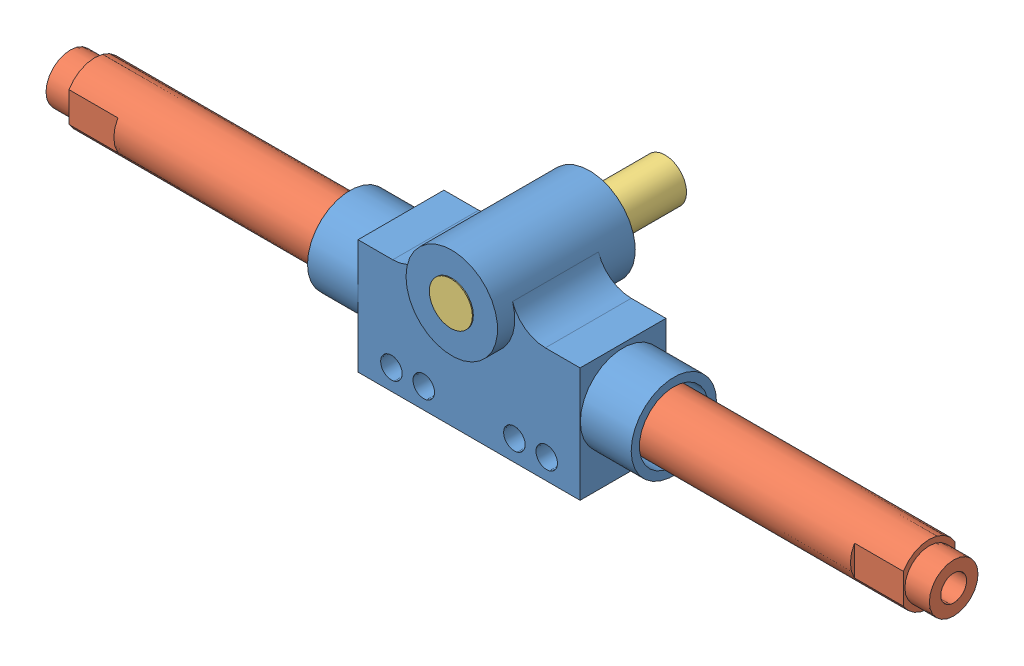
SolidWorks assembly SteeringRack, configuration Default. Lengths in mm.
Overall size (296 62.5 80.5).
3 component instances, 3 part files, 9 mates.
Components (placement in the parent):
- SteeringRackCasting-1: SteeringRackCasting [Default] at (-167.3912 -210.4134 -15.8) size (131.76 62.5 52.7)
- SteeringRackGear-1: SteeringRackGear [Default] at origin size (296 21.6 21.6)
- SteeringPinionGear-1: SteeringPinionGear [Default] at (0 20.65 22.5) x (0 0 -1) z (1 0 0) size (172.28 15.88 15.88)
Mates (geometry in assembly coordinates):
- Coincident1: coincident: plane of SteeringRackCasting-1 through (0 -210.4134 -15.8) normal (1 0 0); plane of assembly through (0 0 0) normal (1 0 0)
- Coincident2: coincident: line of SteeringRackCasting-1 through (131.76 65.88 0) axis (0 -1 0); plane of assembly
- Parallel1: parallel: plane of SteeringRackCasting-1 through (-167.3912 -210.4134 -15.8) normal (0 1 0); plane of assembly through (0 0 0) normal (0 1 0)
- Coincident4: coincident: line of SteeringRackCasting-1 through (131.76 65.88 0) axis (0 -1 0); plane of assembly
- Concentric1: concentric: cylinder of SteeringRackCasting-1 through (-59.55 0 0) axis (1 0 0) radius 12.7; cylinder of SteeringRackGear-1 through (-180.4724 0 0) axis (-1 0 0) radius 10.8
- Distance1: distance = 0 mm: plane of SteeringRackGear-1 through (0 0 0) normal (1 0 0); plane of assembly through (0 0 0) normal (1 0 0)
- Coincident6: coincident: plane of SteeringRackGear-1 through (0 0 0) normal (0 0 1); plane of assembly through (0 0 0) normal (0 0 1)
- Concentric2: concentric: cylinder of SteeringRackCasting-1 through (0 20.65 22.15) axis (0 0 -1) radius 7.9375; cylinder of SteeringPinionGear-1 through (0 20.65 -56.3) axis (0 0 1) radius 7.9375
- Distance2: distance = 27.8 mm: plane of SteeringPinionGear-1 through (0 20.65 -56.3) normal (0 0 -1); plane of SteeringRackCasting-1 through (0 20.65 -28.5) normal (0 0 -1)
